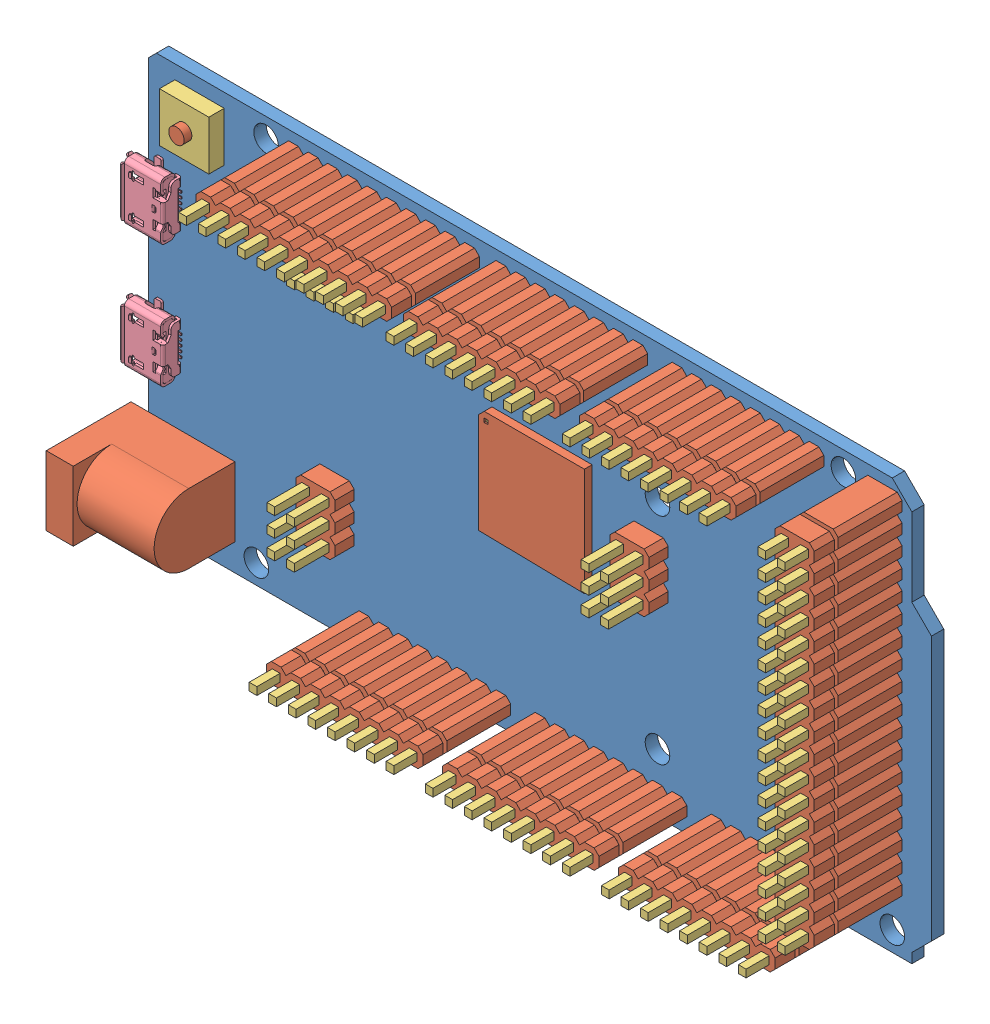
SolidWorks assembly ArduinoDUE, configuration Default. Lengths in mm.
Overall size (103.9 53.34 16).
5 component instances, 4 part files, 1 mates.
Components (placement in the parent):
- PCB-1: PCB [Default] at origin size (101.6 53.34 1.6) (virtual)
- blackPlastic-1: blackPlastic [Default] at origin size (100.09 50.8 11.4) (virtual)
- metal-1: metal [Default] at origin size (95.32 49.5 14.4) (virtual)
- microUSB-1: microUSB [Default] at (1.65 38.0899 1.225) x (0 -1 0) z (-1 0 0) size (7.98 2.94 5.43)
- microUSB-2: microUSB [Default] at (1.65 22.0899 1.225) x (0 -1 0) z (-1 0 0) size (7.98 2.94 5.43)
Mates (geometry in assembly coordinates):
- Coincident22: coincident anti-aligned: plane of PCB-1 through (48.76 101.0999 0) normal (0 0 1); plane of microUSB-2 through (4 24.6864 0) normal (0 0 -1)
